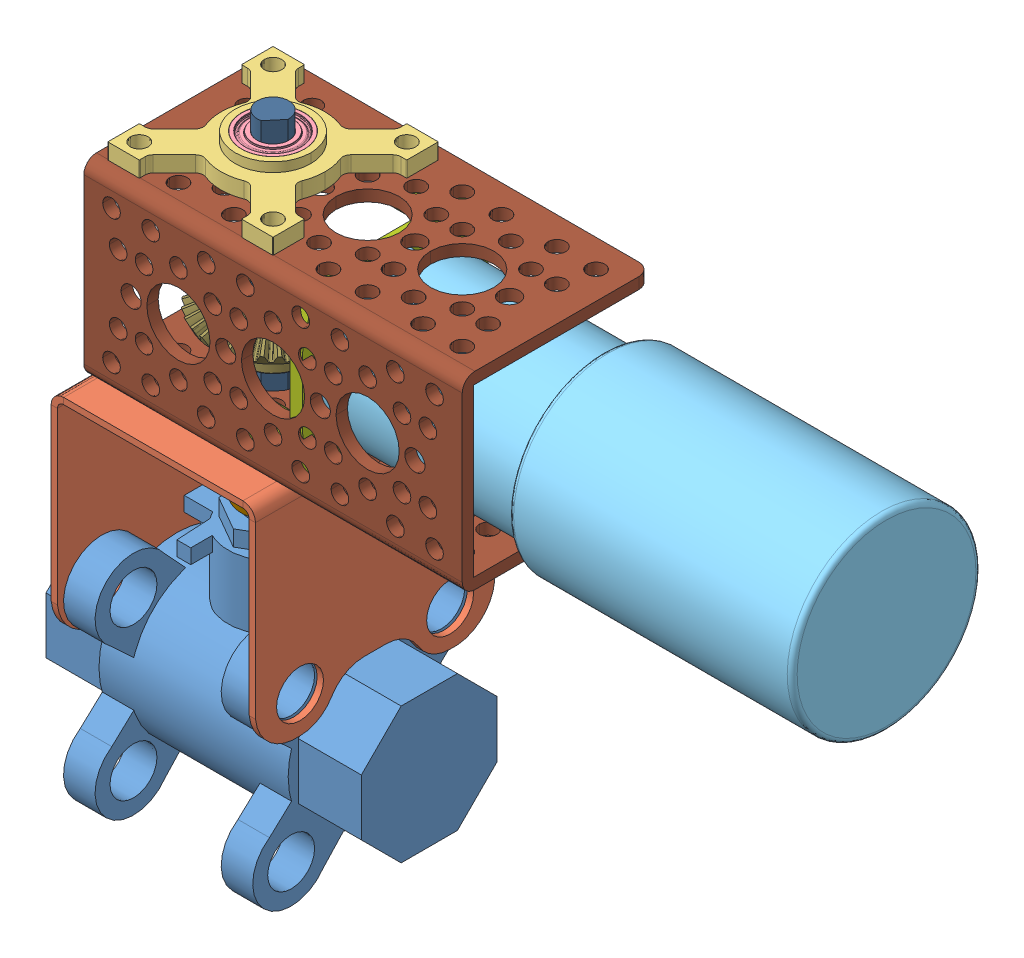
SolidWorks assembly MFV v3 - Trial Fits, configuration Default. Lengths in mm.
Overall size (155.29 121.67 48.16).
19 component instances, 13 part files, 23 mates.
Components (placement in the parent):
- Sharpe 39036-1: Sharpe 39036 [Default] at (-24.652 -21.0473 11.0376) size (63.5 64.02 45.72)
- Base v3-1: Base v3 [Default] at (-5.348 29.6257 11.0376) x (0 0 1) z (1 0 0) size (48.16 44.23 41.15)
- 535110 assembly - Pillow-1: 535110 assembly - Pillow [Default] at (22.7078 53.748 4.1263) x (0 0 1) z (-1 0 0) size (33.27 5.08 33.27)
  - 535110 assembly - Pillow.STEP-1: 535110 assembly - Pillow.STEP [Default] at origin size (33.27 5.08 33.27)
    - 535110.STEP-1: 535110.STEP [Default] at (6.6273 15.2478 28.3097) size (33.27 5.08 33.27)
    - 535020.STEP-1: 535020.STEP [Default] at (6.6273 17.9338 28.3097) size (12.7 4.76 12.7)
- Motor_12VDC_638263-1: Motor_12VDC_638263 [Default] at (16.0368 50.0105 10.7536) x (0 -0.245709 -0.969344) z (0 0.969344 -0.245709) size (38 101.9 38)
- Motor_12VDC_638263_shaft-1: Motor_12VDC_638263_shaft [Default] at (16.0368 50.0105 10.7536) x (0 -0.245709 -0.969344) z (0 0.969344 -0.245709) size (6 16.2 6)
- 555188 assembly.STEP-1: 555188 assembly.STEP [Default] at (20.8107 56.4898 13.3688) x (0 1 0) z (0 0 1) size (33.4 16.56 37.36)
  - 555188.STEP-1: 555188.STEP [Default] at (-6.4793 1.7739 -2.6152) size (33.4 14.22 37.36)
  - 555188 screw_92005A116.STEP-1: 555188 screw_92005A116.STEP [Default] at (-15.6717 7.7739 6.5772) x (1 0 0) z (0 -1 0) size (6 6 8.35)
  - 555188 screw_92005A116.STEP-2: 555188 screw_92005A116.STEP [Default] at (2.7131 7.7739 6.5772) x (0 0 -1) z (0 -1 0) size (6 6 8.35)
  - 555188 screw_92005A116.STEP-3: 555188 screw_92005A116.STEP [Default] at (2.7131 7.7739 -11.8076) x (-1 0 0) z (0 -1 0) size (6 6 8.35)
  - 555188 screw_92005A116.STEP-4: 555188 screw_92005A116.STEP [Default] at (-15.6717 7.7739 -11.8076) x (0 0 1) z (0 -1 0) size (6 6 8.35)
- 625182 assembly-2: 625182 assembly [Default] at (76.2882 0.441 42.7453) x (0.750261 0 0.661142) z (-0.661142 0 0.750261) size (12.69 19.05 12.7)
- D-shaft-2in-1: D-shaft-2in [Default] at (-5.602 20.6122 10.7536) x (0.764496 0 0.644628) z (-0.644628 0 0.764496) size (5.71 57.15 6.35)
- 585442.step-1: 585442.step [Default] at (51.548 30.8957 29.8036) x (0 1 0) z (-1 0 0) size (38.1 38.1 76.2)
- 615444 assembly-1: 615444 assembly [Default] at (-10.1751 11.5237 90.091) x (-0.313058 0 0.949734) z (-0.949734 0 -0.313058) size (26.12 10.1 26.12)
- 615440 assembly-3: 615440 assembly [Default] at (5.0845 74.1995 45.5332) x (0 0.082086 0.996625) z (0 -0.996625 0.082086) size (14.16 11.54 14.16)
Mates (geometry in assembly coordinates):
- Concentric3: concentric: circle of Sharpe 39036-1; circle of Base v3-1
- Concentric4: concentric: cylinder of Sharpe 39036-1 through (13.448 -5.9343 26.1506) axis (-1 0 0) radius 4.7307; circle of Base v3-1
- Coincident4: coincident: plane of Sharpe 39036-1 through (-24.652 -21.0473 11.0376) normal (-1 0 0); plane of Base v3-1 through (-24.652 29.6257 11.0376) normal (1 0 0)
- Concentric8: concentric: circle of Motor_12VDC_638263-1; circle of Motor_12VDC_638263_shaft-1
- Coincident8: coincident: plane of Motor_12VDC_638263-1 through (16.0368 50.0105 10.7536) normal (-1 0 0); plane of Motor_12VDC_638263_shaft-1 through (16.0368 50.0105 10.7536) normal (1 0 0)
- Concentric10: concentric: cylinder of Motor_12VDC_638263-1 through (60.8368 50.0105 10.7536) axis (-1 0 0) radius 16; circle of 555188 assembly.STEP-1/555188.STEP-1
- Distance4: distance = 2.54 mm: plane of Motor_12VDC_638263-1 through (19.0368 50.0105 10.7536) normal (-1 0 0); plane of 555188 assembly.STEP-1/555188.STEP-1 through (16.4968 50.0105 10.7536) normal (-1 0 0)
- Concentric12: concentric: cylinder of Sharpe 39036-1 through (-5.602 20.1165 10.7536) axis (0 -1 0) radius 3.937; cylinder of 625182 assembly-2 through (-5.602 29.6415 10.7536) axis (0 1 0) radius 3.175
- Distance1: distance = 0.254 mm: plane of 625182 assembly-2 through (-5.602 10.5915 10.7536) normal (0 -1 0); plane of Sharpe 39036-1 through (-5.602 10.3375 10.7536) normal (0 1 0)
- Coincident16: coincident: circle of 625182 assembly-2; plane of D-shaft-2in-1 through (-5.602 20.6122 10.7536) normal (0 -1 0)
- Concentric13: concentric: cylinder of 625182 assembly-2 through (-5.602 29.6415 10.7536) axis (0 1 0) radius 3.175; cylinder of D-shaft-2in-1 through (-5.602 77.7622 10.7536) axis (0 -1 0) radius 3.175
- Concentric17: concentric: circle of Sharpe 39036-1; circle of 585442.step-1
- Coincident20: coincident: plane of Base v3-1 through (-5.348 30.8957 11.0376) normal (0 1 0); plane of 585442.step-1 through (-24.652 30.8957 29.8036) normal (0 -1 0)
- Concentric18: concentric: cylinder of 535110 assembly - Pillow-1/535110 assembly - Pillow.STEP-1/535020.STEP-1 through (-5.602 74.063 10.7536) axis (0 -1 0) radius 3.175; cylinder of D-shaft-2in-1 through (-5.602 77.7622 10.7536) axis (0 -1 0) radius 3.175
- Concentric19: concentric: circle of 535110 assembly - Pillow-1/535110 assembly - Pillow.STEP-1/535110.STEP-1; circle of 585442.step-1
- Coincident23: coincident: plane of 535110 assembly - Pillow-1/535110 assembly - Pillow.STEP-1/535110.STEP-1 through (-5.602 68.9957 10.7536) normal (0 -1 0); plane of 585442.step-1 through (-24.652 68.9957 -8.2964) normal (0 1 0)
- Perpendicular1: perpendicular: line of Base v3-1 through (-23.382 30.8957 35.1168) axis (0 0 -1); line of 585442.step-1 through (-22.112 33.1817 -8.2964) axis (1 0 0)
- Parallel5: parallel: cylinder of Motor_12VDC_638263-1 through (117.9368 50.0105 10.7536) axis (-1 0 0) radius 19; line of 585442.step-1 through (-22.112 68.9957 -8.2964) axis (1 0 0)
- Parallel6: parallel: plane of 555188 assembly.STEP-1/555188.STEP-1 through (16.4968 66.7097 27.2128) normal (0 1 0); plane of 585442.step-1 through (-24.652 66.7097 27.5176) normal (0 -1 0)
- Coincident24: coincident: plane of 555188 assembly.STEP-1/555188.STEP-1 through (16.4968 66.7097 27.2128) normal (0 1 0); plane of 585442.step-1 through (-24.652 66.7097 27.5176) normal (0 -1 0)
- Concentric26: concentric: cylinder of D-shaft-2in-1 through (-5.602 77.7622 10.7536) axis (0 -1 0) radius 3.175; cylinder of 615444 assembly-1 through (-5.602 45.1732 10.7536) axis (0 1 0) radius 3.175
- Concentric27: concentric: circle of 535110 assembly - Pillow-1/535110 assembly - Pillow.STEP-1/535110.STEP-1; circle of 555188 assembly.STEP-1/555188.STEP-1
- Concentric28: concentric: cylinder of Motor_12VDC_638263_shaft-1 through (-0.1632 50.0105 10.7536) axis (1 0 0) radius 3; cylinder of 615440 assembly-3 through (2.5318 50.0105 10.7536) axis (-1 0 0) radius 3
